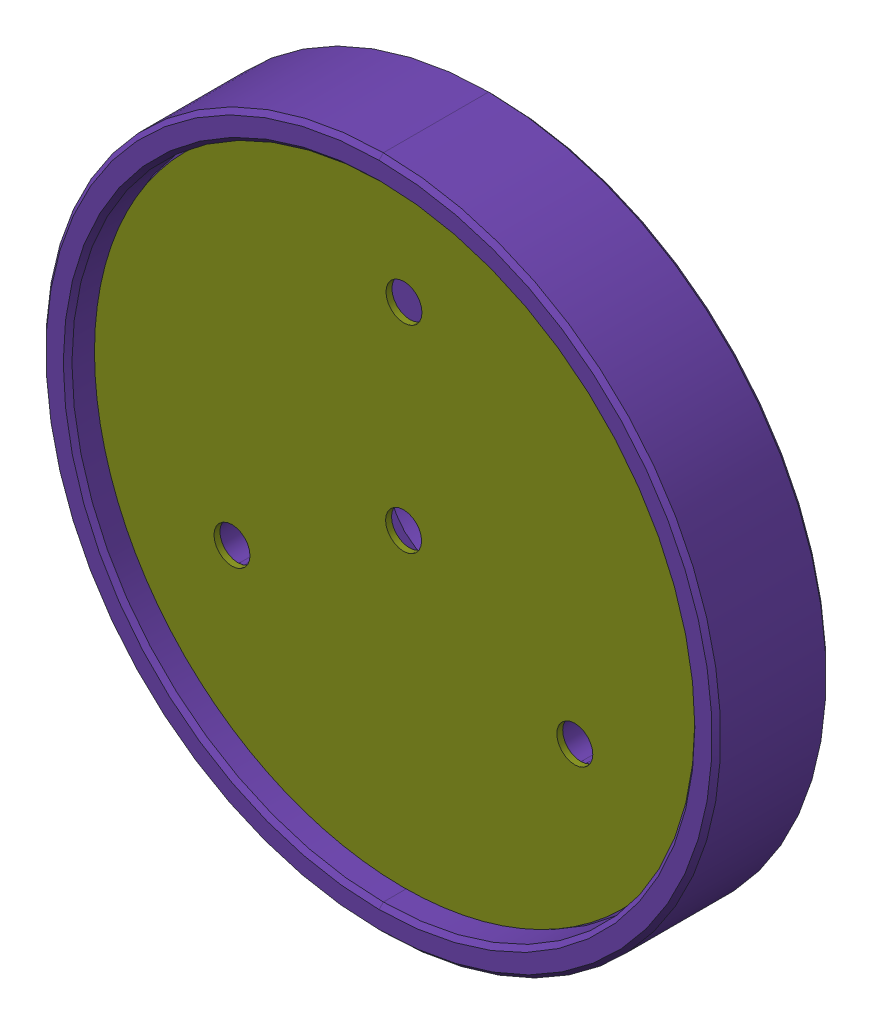
SolidWorks assembly 装配效果, configuration 默认. Lengths in mm.
Overall size (46.8 46.8 7.9).
54 component instances, 17 part files, 2 mates.
Components (placement in the parent):
- PCB-Bottom.step-1: PCB-Bottom.step [默认] at (123.2153 -76.7744 -1.6885) x (0.001982 0.999998 0) z (0 0 1) size (42.87 42.87 2.41)
  - BUZZER1.step-1: BUZZER1.step [默认] at origin size (5.2 5.2 2.1)
    - BEEP_5020.step-1: BEEP_5020.step [默认] at (104.113 94.107 -0.4115) x (0 -1 0) z (1 0 0) size (5.2 2.1 5.2)
  - R1.step-1: R1.step [默认] at origin size (1.15 0.55 0.41)
    - User_Library-RES_1005-0402.step-1: User_Library-RES_1005-0402.step [默认] at (105.791 90.424 -0.4115) x (1 0 0) z (0 1 0) size (1.15 0.41 0.55)
  - D3.step-1: D3.step [默认] at origin size (1.6 0.8 0.6)
    - User_Library-LED_0603_R.step-1: User_Library-LED_0603_R.step [默认] at (102.9971 90.4239 -0.4115) x (1 0 0) z (0 0 -1) size (1.6 0.8 0.6)
      - User_Library-LED_0603_R_Pocket002.step-1: User_Library-LED_0603_R_Pocket002.step [默认] at origin size (0.4 0.8 0.2)
      - User_Library-LED_0603_R_Pad004.step-1: User_Library-LED_0603_R_Pad004.step [默认] x (1 0 0) z (0 0 -1) size (0.4 0.8 0)
      - User_Library-LED_0603_R_Fillet.step-1: User_Library-LED_0603_R_Fillet.step [默认] at origin size (1 0.7 0.4)
      - User_Library-LED_0603_R_Pocket001.step-1: User_Library-LED_0603_R_Pocket001.step [默认] at origin size (0.4 0.8 0.2)
      - User_Library-LED_0603_R_Pad.step-1: User_Library-LED_0603_R_Pad.step [默认] at origin size (0.8 0.8 0.2)
  - D1.step-1: D1.step [默认] at origin size (3.7 1.6 1.43)
    - SOD123.step-1: SOD123.step [默认] at (99.8218 104.0132 -0.4115) x (-1 0 0) z (0 0 -1) size (3.7 1.6 1.43)
  - Q1.step-1: Q1.step [默认] at origin size (6.1 5.1 1)
    - 657818720.step-1: 657818720.step [默认] at (87.376 99.822 -1.4615) size (6.1 5.1 1)
      - Extruded.step-1: Extruded.step [默认] at origin size (6.1 5.1 1)
  - Q2.step-1: Q2.step [默认] at origin size (6.1 5.1 1)
    - 657818720.step-1: 657818720.step [默认] at (87.376 105.41 -1.4615) size (6.1 5.1 1)
      - Extruded.step-1: Extruded.step [默认] at origin size (6.1 5.1 1)
  - Q3.step-1: Q3.step [默认] at origin size (6.1 5.1 1)
    - 657818720.step-1: 657818720.step [默认] at (87.376 94.234 -1.4615) size (6.1 5.1 1)
      - Extruded.step-1: Extruded.step [默认] at origin size (6.1 5.1 1)
  - D2.step-1: D2.step [默认] at origin size (1.6 3.7 1.43)
    - SOD123.step-1: SOD123.step [默认] at (97.9168 93.7258 -0.4115) x (0 -1 0) z (0 0 -1) size (3.7 1.6 1.43)
  - R2.step-1: R2.step [默认] at origin size (1.25 2 0.5)
    - User_Library-R_0805.step-1: User_Library-R_0805.step [默认] at (99.949 94.8723 -0.4015) x (0 1 0) z (0 0 -1) size (2 1.25 0.5)
  - R3.step-1: R3.step [默认] at origin size (0.55 1.15 0.41)
    - User_Library-RES_1005-0402.step-1: User_Library-RES_1005-0402.step [默认] at (96.393 92.71 -0.4115) x (0 1 0) z (-1 0 0) size (1.15 0.41 0.55)
  - C1.step-1: C1.step [默认] at origin size (0.8 1.6 0.3)
    - User_Library-0603_SMD_Capacitor.step-1: User_Library-0603_SMD_Capacitor.step [默认] at (97.536 107.315 -0.4115) x (0 1 0) z (-1 0 0) size (1.6 0.3 0.8)
  - C2.step-1: C2.step [默认] at origin size (0.8 1.6 0.3)
    - User_Library-0603_SMD_Capacitor.step-1: User_Library-0603_SMD_Capacitor.step [默认] at (104.902 107.442 -0.4115) x (0 1 0) z (-1 0 0) size (1.6 0.3 0.8)
  - VR1.step-1: VR1.step [默认] at origin size (4.3 4.5 1.51)
    - SOT-89-3.step-1: SOT-89-3.step [默认] at (100.6181 107.4419 -0.4115) x (0 1 0) z (0 0 -1) size (4.5 4.3 1.51)
  - C3.step-1: C3.step [默认] at origin size (1 0.6 0.2)
    - 0402_SMD_Capacitor.step-1: 0402_SMD_Capacitor.step [默认] at (105.0464 102.87 -0.4115) x (1 0 0) z (0 1 0) size (1 0.2 0.6)
  - C4.step-1: C4.step [默认] at origin size (1 0.6 0.2)
    - 0402_SMD_Capacitor.step-1: 0402_SMD_Capacitor.step [默认] at (106.5704 97.536 -0.4115) x (1 0 0) z (0 1 0) size (1 0.2 0.6)
  - R4.step-1: R4.step [默认] at origin size (1.15 0.55 0.41)
    - User_Library-RES_1005-0402.step-1: User_Library-RES_1005-0402.step [默认] at (104.267 97.536 -0.4115) x (1 0 0) z (0 1 0) size (1.15 0.41 0.55)
  - U1.step-1: U1.step [默认] at origin size (2.92 2.84 1.12)
    - DBV0006AakaMF06A.step-1: DBV0006AakaMF06A.step [默认] at (105.4099 100.2029 -1.2615) x (-1 0 0) z (0 -1 0) size (2.92 1.12 2.84)
      - BODY_MF06A.step-1: BODY_MF06A.step [默认] at origin size (2.92 1.02 1.6)
      - LEAD_MF06A.step-1: LEAD_MF06A.step [默认] at (0.9525 -0.6604 0.9652) size (0.37 0.86 0.62)
      - LEAD_MF06A.step-2: LEAD_MF06A.step [默认] at (0 -0.6604 0.9652) size (0.37 0.86 0.62)
      - LEAD_MF06A.step-3: LEAD_MF06A.step [默认] at (-0.9525 -0.6604 0.9652) size (0.37 0.86 0.62)
      - LEAD_MF06A.step-4: LEAD_MF06A.step [默认] at (0.9525 -0.6604 -0.9652) x (-1 0 0) z (0 0 -1) size (0.37 0.86 0.62)
      - LEAD_MF06A.step-5: LEAD_MF06A.step [默认] at (0 -0.6604 -0.9652) x (-1 0 0) z (0 0 -1) size (0.37 0.86 0.62)
      - LEAD_MF06A.step-6: LEAD_MF06A.step [默认] at (-0.9525 -0.6604 -0.9652) x (-1 0 0) z (0 0 -1) size (0.37 0.86 0.62)
  - C5.step-1: C5.step [默认] at origin size (0.6 1 0.2)
    - 0402_SMD_Capacitor.step-1: 0402_SMD_Capacitor.step [默认] at (107.696 94.1244 -0.4115) x (0 1 0) z (-1 0 0) size (1 0.2 0.6)
  - Board.step-1: Board.step [默认] at (0 0 -0.4115) size (42.87 42.87 0.41)
- 底部铝合金导电外壳_1-修改-1: 底部铝合金导电外壳_1-修改 [默认] at origin size (46.8 46.8 7.9)
Mates (geometry in assembly coordinates):
- 同心2: concentric: circle of PCB-Bottom.step-1/Board.step-1; circle of 底部铝合金导电外壳_1-修改-1
- 重合3: coincident aligned: plane of PCB-Bottom.step-1/Board.step-1 through (44.8069 24.7832 -2.1) normal (0 0 -1); circle of 底部铝合金导电外壳_1-修改-1
